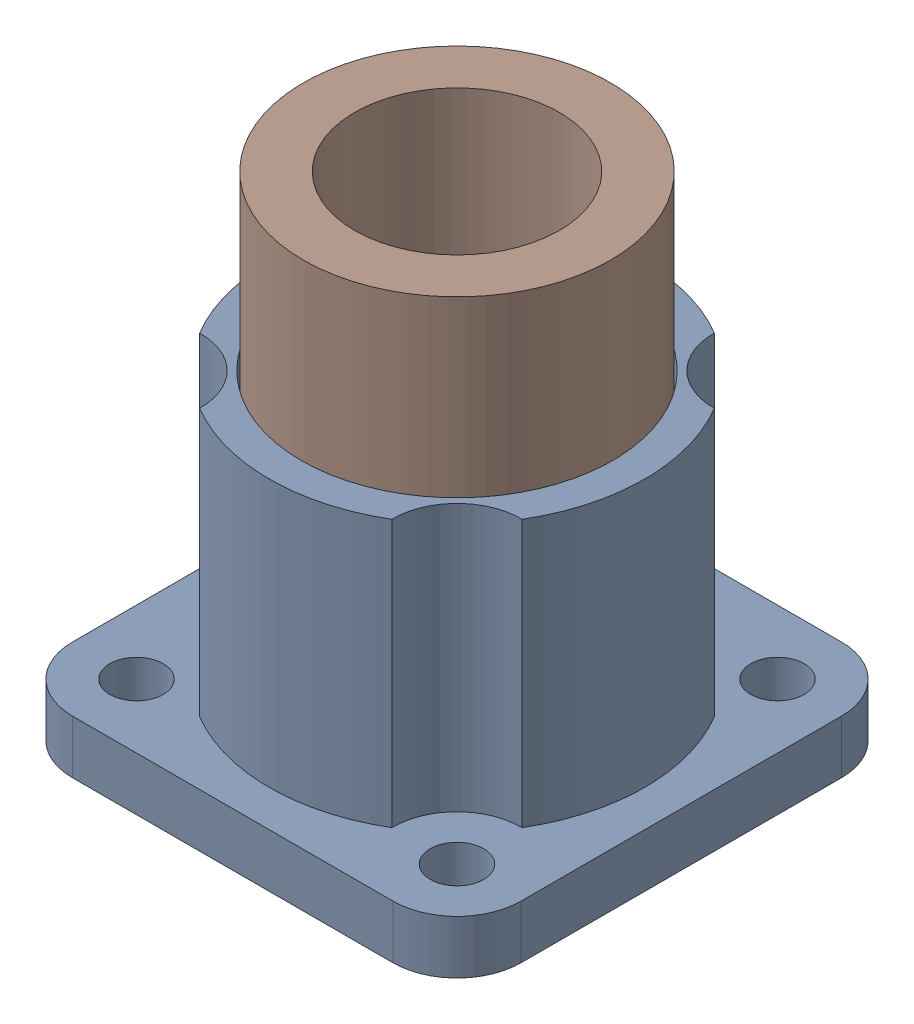
SolidWorks assembly turntable_bearing_assembly, configuration Default. Lengths in mm.
Overall size (42 46.15 42).
3 component instances, 3 part files, 0 mates.
Components (placement in the parent):
- turntable_support_bearing-1: turntable_support_bearing [Default] at (-21.9394 -6.1414 5.5587) size (42 30 42)
- D25_bearings-1: D25_bearings [Default] at (-34.7962 11.1659 5.5492) size (27.9 2.5 27.76)
- turntable_support_bearing_top-1: turntable_support_bearing_top [Default] at (-21.9394 25.0098 5.5587) x (0.999961 0 -0.008878) z (0.008878 0 0.999961) size (28.76 28.61 28.76)
